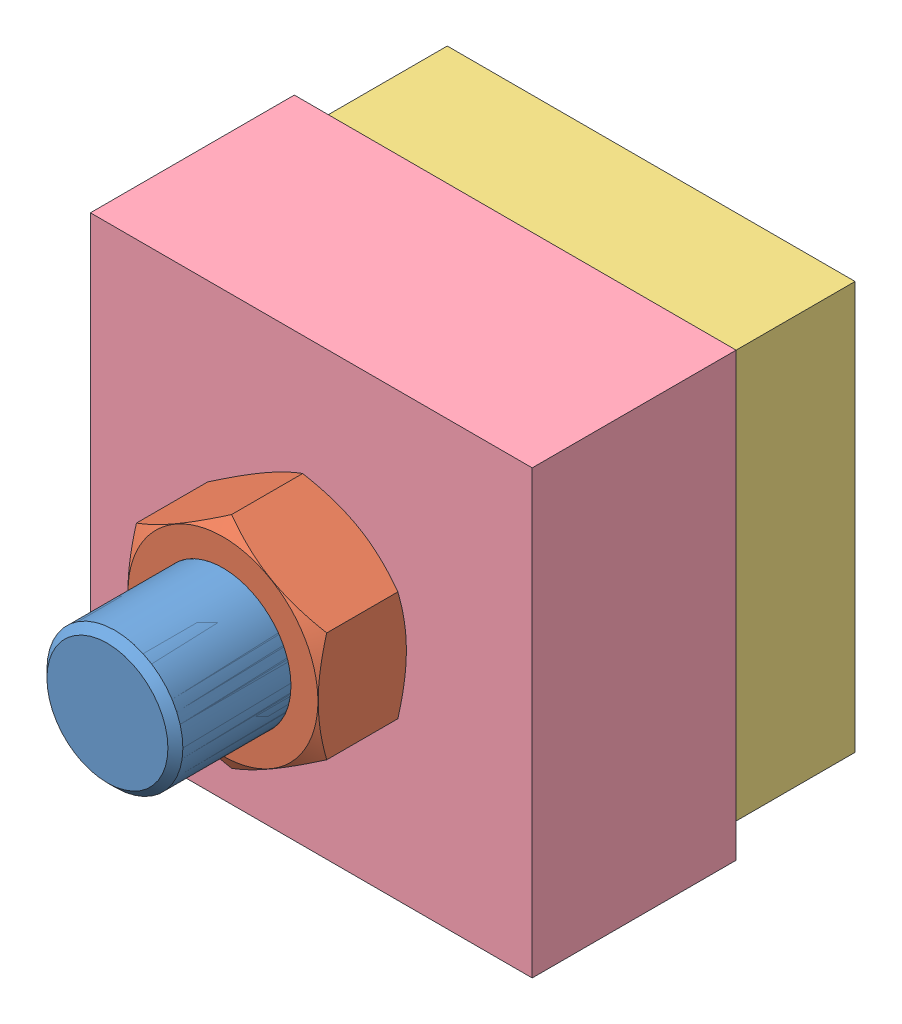
SolidWorks assembly Сборка_гайка-болт, configuration По умолчанию. Lengths in mm.
Overall size (65 65 93).
4 component instances, 4 part files, 10 mates.
Components (placement in the parent):
- Болт-1: Болт [По умолчанию] at origin size (28.58 33 93)
- Гайка-1: Гайка [По умолчанию] at (0 0 63) size (28 32.33 13)
- Пластина 1-1: Пластина 1 [По умолчанию] at (-30 -30 20) size (60 60 20)
- Пластина 2-1: Пластина 2 [По умолчанию] at (0 0 20) size (65 65 30)
Mates (geometry in assembly coordinates):
- Совпадение1: coordinate: point of Болт-1; point of assembly
- Концентричный1: concentric anti-aligned: cylinder of Болт-1 through (0 0 80) axis (0 0 -1) radius 10; cylinder of Гайка-1 through (0 0 50) axis (0 0 1) radius 8.8985
- Совпадение2: coincident anti-aligned: plane of Пластина 2-1 through (0 0 50) normal (0 0 1); plane of Гайка-1 through (0 0 50) normal (0 0 -1)
- Параллельность1: parallel aligned: plane of Болт-1 through (-14.2894 8.25 -13) normal (-1 0 0); plane of Гайка-1 through (-14 8.0829 50) normal (-1 0 0)
- Концентричный2: concentric anti-aligned: cylinder of Болт-1 through (0 0 80) axis (0 0 -1) radius 10; cylinder of Пластина 1-1 through (0 0 0) axis (0 0 1) radius 11
- Концентричный3: concentric aligned: cylinder of Болт-1 through (0 0 80) axis (0 0 -1) radius 10; cylinder of Пластина 2-1 through (0 0 50) axis (0 0 -1) radius 11
- Совпадение3: coincident anti-aligned: plane of Болт-1 through (0 0 0) normal (0 0 1); plane of Пластина 1-1 through (-30 -30 0) normal (0 0 -1)
- Совпадение4: coincident anti-aligned: plane of Пластина 1-1 through (-30 -30 20) normal (0 0 1); plane of Пластина 2-1 through (0 0 20) normal (0 0 -1)
- Параллельность2: parallel aligned: plane of Болт-1 through (14.2894 -8.25 -13) normal (1 0 0); plane of Пластина 1-1 through (30 -30 0) normal (1 0 0)
- Параллельность3: parallel aligned: plane of Болт-1 through (14.2894 -8.25 -13) normal (1 0 0); plane of Пластина 2-1 through (32.5 -32.5 50) normal (1 0 0)
